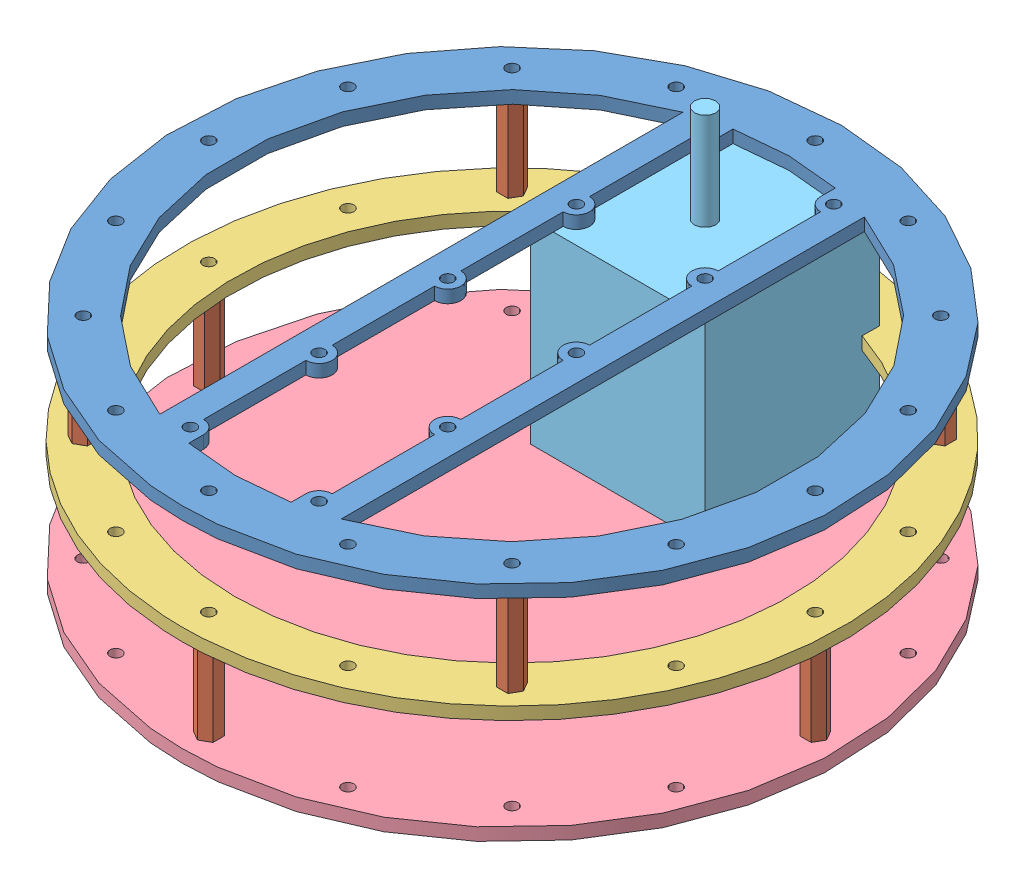
SolidWorks assembly HousingSteppeMotor, configuration Default. Lengths in mm.
Overall size (158.75 74.02 158.75).
13 component instances, 6 part files, 16 mates.
Components (placement in the parent):
- Base Unit-1: Base Unit [Default] at (-15.6008 25.016 -9.7985) size (158.75 3.05 158.75)
- Part11^HousingSteppeMotor-1: Part11^HousingSteppeMotor [Default] at origin (virtual)
- LHexStandoff-1: LHexStandoff [Default] at (-18.4264 2.7402 134.3541) x (0.866025 0 -0.5) z (0 1 0) size (5.46 4.72 22.28)
- LHexStandoff-2: LHexStandoff [Default] at (128.5518 2.7402 -6.9729) x (-0.5 0 -0.866025) z (0 1 0) size (5.46 4.72 22.28)
- LHexStandoff-3: LHexStandoff [Default] at (-12.7752 2.7402 -153.9512) x (-0.866025 0 0.5) z (0 1 0) size (5.46 4.72 22.28)
- LHexStandoff-4: LHexStandoff [Default] at (-159.7534 2.7402 -12.6242) x (0.5 0 0.866025) z (0 1 0) size (5.46 4.72 22.28)
- Generic Unit-1: Generic Unit [Default] at (-15.6008 -0.3078 -9.7985) size (158.75 3.05 158.75)
- LHexStandoff-5: LHexStandoff [Default] at (33.21 -22.5836 9.6926) x (0.866025 0 -0.5) z (0 1 0) size (5.46 4.72 22.28)
- LHexStandoff-6: LHexStandoff [Default] at (3.8904 -22.5836 -58.6094) x (-0.5 0 -0.866025) z (0 1 0) size (5.46 4.72 22.28)
- LHexStandoff-7: LHexStandoff [Default] at (-64.4116 -22.5836 -29.2897) x (-0.866025 0 0.5) z (0 1 0) size (5.46 4.72 22.28)
- LHexStandoff-8: LHexStandoff [Default] at (-35.092 -22.5836 39.0123) x (0.5 0 0.866025) z (0 1 0) size (5.46 4.72 22.28)
- Bottom Panel-1: Bottom Panel [Default] at (-15.6008 -25.6316 -9.7985) size (158.75 3.05 158.75)
- Stepper mock uo-1: Stepper mock uo [Default] at (-15.5754 1.521 -56.2559) x (1 0 0) z (0 1 0) size (42.01 42.01 70.36)
Mates (geometry in assembly coordinates):
- Concentric1: concentric aligned: circle of Base Unit-1; circle of LHexStandoff-1
- Coincident1: coincident anti-aligned: plane of Base Unit-1 through (-15.6008 25.016 -9.7985) normal (0 -1 0); plane of LHexStandoff-1 through (-18.4264 25.016 134.3541) normal (0 1 0)
- Parallel1: parallel: line of LHexStandoff-1 through (-69.5995 2.7402 40.4741) axis (0 0 1); plane of assembly
- Concentric2: concentric aligned: circle of LHexStandoff-4; circle of Generic Unit-1
- Concentric3: concentric aligned: circle of LHexStandoff-3; circle of Generic Unit-1
- Coincident3: coincident anti-aligned: plane of LHexStandoff-3 through (-12.7752 2.7402 -153.9512) normal (0 -1 0); plane of Generic Unit-1 through (-15.6008 2.7402 -9.7985) normal (0 1 0)
- Concentric4: concentric aligned: circle of Generic Unit-1; circle of LHexStandoff-5
- Coincident4: coincident anti-aligned: plane of Generic Unit-1 through (-15.6008 -0.3078 -9.7985) normal (0 -1 0); plane of LHexStandoff-5 through (33.21 -0.3078 9.6926) normal (0 1 0)
- Parallel2: parallel anti-aligned: plane of Base Unit-1 through (6.2432 25.016 -9.7985) normal (1 0 0); plane of LHexStandoff-5 through (-17.963 -0.3078 -84.1873) normal (-1 0 0)
- Concentric5: concentric aligned: circle of LHexStandoff-7; circle of Bottom Panel-1
- Coincident6: coincident anti-aligned: plane of LHexStandoff-6 through (3.8904 -22.5836 -58.6094) normal (0 -1 0); plane of Bottom Panel-1 through (-15.6008 -22.5836 -9.7985) normal (0 1 0)
- Concentric6: concentric aligned: circle of LHexStandoff-6; circle of Bottom Panel-1
- Concentric7: concentric aligned: cylinder of Base Unit-1 through (-15.6008 28.064 -9.7985) axis (0 -1 0) radius 79.375; cylinder of Generic Unit-1 through (-15.6008 2.7402 -9.7985) axis (0 -1 0) radius 79.375
- Concentric8: concentric: circle of Base Unit-1; circle of Stepper mock uo-1
- Coincident8: coincident: plane of Base Unit-1 through (-15.6008 25.016 -9.7985) normal (0 -1 0); plane of Stepper mock uo-1 through (-15.5244 25.016 -56.2053) normal (0 1 0)
- Parallel3: parallel aligned: plane of Base Unit-1 through (-37.4448 25.016 -9.7985) normal (-1 0 0); plane of Stepper mock uo-1 through (-36.5812 25.016 -77.2609) normal (-1 0 0)
